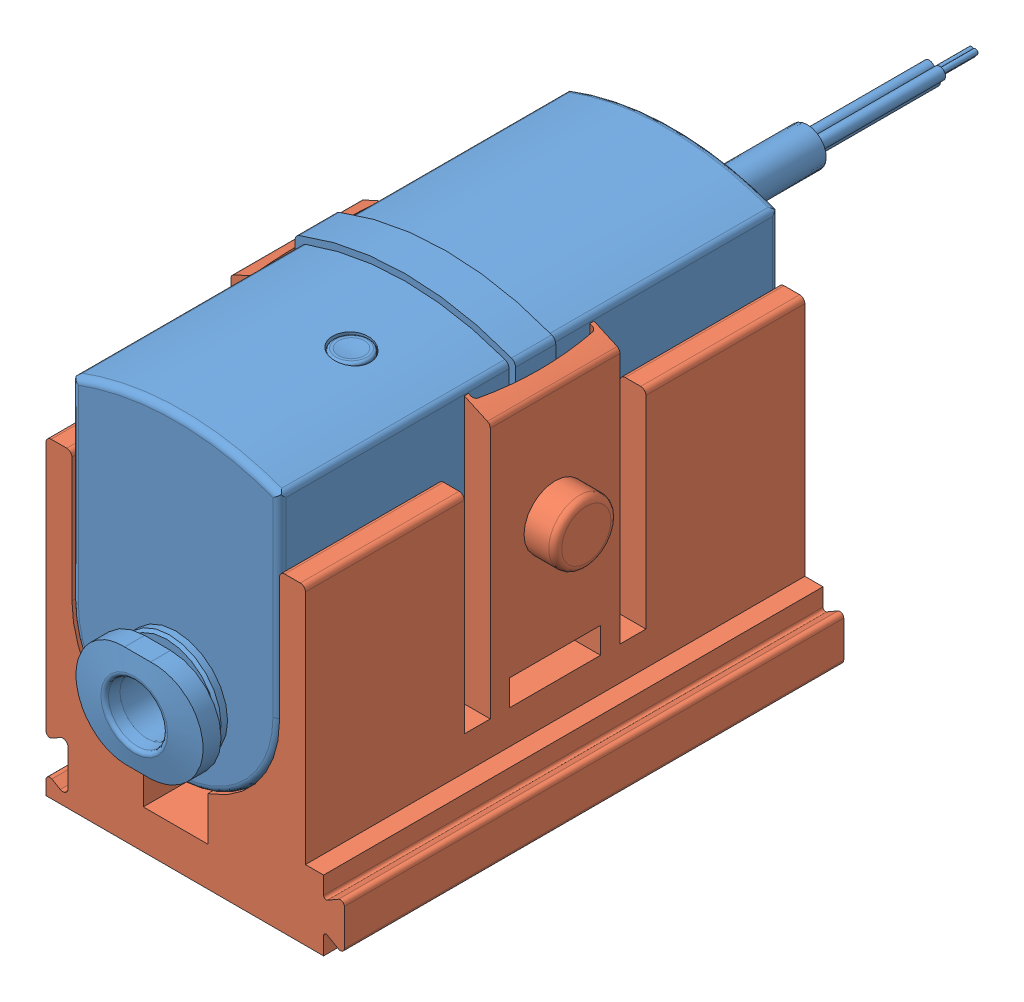
SolidWorks assembly 529027 SDE5-D10-FP-Q4-P-K---(asm), configuration Default. Lengths in mm.
Overall size (38.5 39.89 64.7).
2 component instances, 2 part files, 0 mates.
Components (placement in the parent):
- 529027 SDE5-Q4-K(FP)---(DS)-1: 529027 SDE5-Q4-K(FP)---(DS) [Default] x (0 0 -1) z (1 0 0) size (64.7 25.5 18)
- 653056 SDE5---(H)-1: 653056 SDE5---(H) [Default] at (0 -6 0) x (0 0 -1) z (1 0 0) size (38.5 29.77 23)
